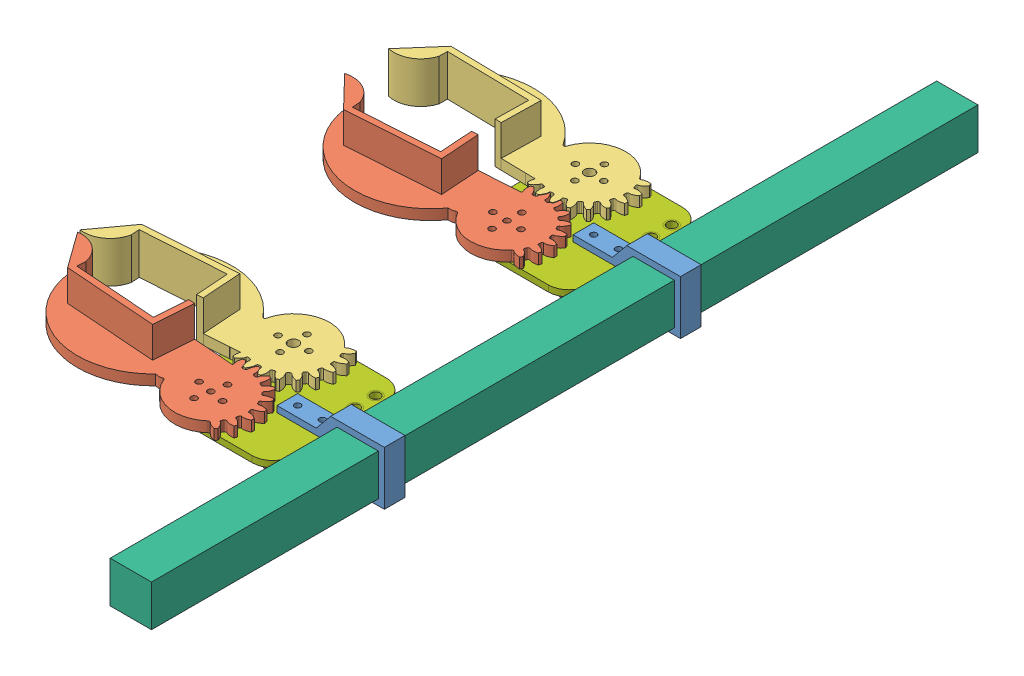
SolidWorks assembly 抓手装配体v1.0, configuration Default. Lengths in mm.
Overall size (156.58 65.63 400).
13 component instances, 7 part files, 36 mates.
Components (placement in the parent):
- M2X20连接件-1: M2X20连接件 [默认] at (-24.8405 13.5666 280.2912) size (52 26 10)
- 右臂直齿M2X20-1: 右臂直齿M2X20 [M2X20] at (-68.8405 21.9166 160.9702) x (0.069464 0 0.997584) z (0 -1 0) size (42.85 107.25 20)
- 左臂直齿M2X20-1: 左臂直齿M2X20 [M2X20] at (-68.8405 17.1166 120.9702) x (0.019311 0 -0.999814) z (0 1 0) size (42.67 107.08 20)
- 35KGservo-2: 35KGservo [默认] at (-58.8405 -8.3834 120.9702) x (-1 0 0) z (0 0 -1) size (62.21 45.03 20.04)
- 舵机圆形头-2: 舵机圆形头 [默认] at (-58.8413 -8.8611 121.095) x (-0.999922 0 -0.012481) z (0.012481 0 -0.999922) size (19.5 4.4 19.5)
- 横杆的简易模型-2: 横杆的简易模型 [默认] at origin size (20 20 400)
- M2X20连接件-2: M2X20连接件 [默认] at (-24.8405 13.4666 136.9702) size (52 26 10)
- M2X20固定舵机盘-3: M2X20固定舵机盘 [默认] at (-23.324 15.0176 132.5027) x (-1 0 0) z (0 -1 0) size (60 65 4.9)
- 右臂直齿M2X20-3: 右臂直齿M2X20 [M2X20] at (-68.8405 22.0166 304.2912) x (-0.073101 0 0.997325) z (0 -1 0) size (42.85 107.25 20)
- 35KGservo-4: 35KGservo [默认] at (-58.8405 -8.2834 264.2912) x (-1 0 0) z (0 0 -1) size (62.21 45.03 20.04)
- 左臂直齿M2X20-3: 左臂直齿M2X20 [M2X20] at (-68.8405 17.2166 264.2912) x (-0.067789 0 -0.9977) z (0 1 0) size (42.67 107.08 20)
- 舵机圆形头-4: 舵机圆形头 [默认] at (-58.8684 -8.7611 263.5451) x (-0.997213 0 0.074603) z (-0.074603 0 -0.997213) size (19.5 4.4 19.5)
- M2X20固定舵机盘-4: M2X20固定舵机盘 [默认] at (-23.324 15.1176 275.8237) x (-1 0 0) z (0 -1 0) size (60 65 4.9)
Mates (geometry in assembly coordinates):
- 重合5: coincident anti-aligned: plane of 35KGservo-2 through (-58.8405 13.1166 120.9702) normal (0 1 0); plane of 舵机圆形头-2 through (-68.8405 13.1166 120.9702) normal (0 -1 0)
- 同心4: concentric anti-aligned: circle of 35KGservo-2; circle of 舵机圆形头-2
- 同心5: concentric aligned: circle of 舵机圆形头-2; circle of M2X20固定舵机盘-3
- 同心7: concentric anti-aligned: cylinder of 35KGservo-2 through (-34.0905 6.0166 125.9702) axis (0 1 0) radius 2.25; cylinder of M2X20固定舵机盘-3 through (-34.0905 15.0176 125.9702) axis (0 -1 0) radius 2.25
- 重合24: coincident anti-aligned: plane of 35KGservo-2 through (-58.8405 12.0166 120.9702) normal (0 1 0); plane of M2X20固定舵机盘-3 through (-23.324 12.0166 132.5027) normal (0 -1 0)
- 重合29: coincident anti-aligned: plane of 左臂直齿M2X20-1 through (-68.8405 17.1166 120.9702) normal (0 -1 0); plane of 舵机圆形头-2 through (-68.8405 17.1166 120.9702) normal (0 1 0)
- 同心15: concentric anti-aligned: cylinder of 左臂直齿M2X20-1 through (-68.8405 22.1166 120.9702) axis (0 -1 0) radius 2.5; circle of 舵机圆形头-2
- 同心16: concentric anti-aligned: circle of 左臂直齿M2X20-1; circle of 舵机圆形头-2
- 重合30: coincident anti-aligned: plane of 右臂直齿M2X20-1 through (-68.8405 16.9166 160.9702) normal (0 -1 0); plane of M2X20固定舵机盘-3 through (-68.8405 16.9166 160.9702) normal (0 1 0)
- 同心17: concentric aligned: cylinder of 右臂直齿M2X20-1 through (-68.8405 16.9166 160.9702) axis (0 1 0) radius 1.5; cylinder of M2X20固定舵机盘-3 through (-68.8405 12.0166 160.9702) axis (0 1 0) radius 2.5
- 同心18: concentric anti-aligned: cylinder of 左臂直齿M2X20-1 through (-61.8418 22.1166 121.1054) axis (0 -1 0) radius 1.5; circle of 舵机圆形头-2
- 重合39: coincident anti-aligned: plane of M2X20连接件-1 through (-21.8405 3.4666 260.2912) normal (0 1 0); plane of 横杆的简易模型-2 through (-1.8405 3.4666 400) normal (0 -1 0)
- 重合40: coincident anti-aligned: plane of M2X20连接件-1 through (-21.8405 23.5666 260.2912) normal (1 0 0); plane of 横杆的简易模型-2 through (-21.8405 23.4666 400) normal (-1 0 0)
- 重合41: coincident anti-aligned: plane of 横杆的简易模型-2 through (-21.8405 23.4666 400) normal (-1 0 0); plane of M2X20连接件-2 through (-21.8405 23.4666 116.9702) normal (1 0 0)
- 重合42: coincident anti-aligned: plane of 横杆的简易模型-2 through (-21.8405 23.4666 400) normal (0 1 0); plane of M2X20连接件-2 through (-1.7405 23.4666 116.9702) normal (0 -1 0)
- 重合46: coincident anti-aligned: plane of M2X20连接件-2 through (-50.8405 15.0166 146.9702) normal (0 -1 0); plane of M2X20固定舵机盘-3 through (-23.324 15.0166 132.5027) normal (0 1 0)
- 锁定2: lock: unknown of 横杆的简易模型-2; unknown of M2X20连接件-2
- 锁定3: lock: unknown of M2X20连接件-1; unknown of 横杆的简易模型-2
- 同心21: concentric aligned: circle of 舵机圆形头-4; circle of M2X20固定舵机盘-4
- 同心22: concentric anti-aligned: cylinder of 35KGservo-4 through (-34.0905 6.1166 269.2912) axis (0 1 0) radius 2.25; cylinder of M2X20固定舵机盘-4 through (-34.0905 15.1176 269.2912) axis (0 -1 0) radius 2.25
- 同心23: concentric anti-aligned: cylinder of 左臂直齿M2X20-3 through (-68.8405 22.2166 264.2912) axis (0 -1 0) radius 2.5; circle of 舵机圆形头-4
- 重合50: coincident anti-aligned: plane of 35KGservo-4 through (-58.8405 13.2166 264.2912) normal (0 1 0); plane of 舵机圆形头-4 through (-68.8405 13.2166 264.2912) normal (0 -1 0)
- 同心24: concentric anti-aligned: circle of 35KGservo-4; circle of 舵机圆形头-4
- 同心25: concentric anti-aligned: circle of 左臂直齿M2X20-3; circle of 舵机圆形头-4
- 同心26: concentric aligned: cylinder of 右臂直齿M2X20-3 through (-68.8405 17.0166 304.2912) axis (0 1 0) radius 1.5; cylinder of M2X20固定舵机盘-4 through (-68.8405 12.1166 304.2912) axis (0 1 0) radius 2.5
- 重合51: coincident anti-aligned: plane of 右臂直齿M2X20-3 through (-68.8405 17.0166 304.2912) normal (0 -1 0); plane of M2X20固定舵机盘-4 through (-68.8405 17.0166 304.2912) normal (0 1 0)
- 同心27: concentric anti-aligned: cylinder of 左臂直齿M2X20-3 through (-61.8566 22.2166 263.8166) axis (0 -1 0) radius 1.5; circle of 舵机圆形头-4
- 重合52: coincident anti-aligned: plane of 左臂直齿M2X20-3 through (-68.8405 17.2166 264.2912) normal (0 -1 0); plane of 舵机圆形头-4 through (-68.8405 17.2166 264.2912) normal (0 1 0)
- 重合53: coincident anti-aligned: plane of 35KGservo-4 through (-58.8405 12.1166 264.2912) normal (0 1 0); plane of M2X20固定舵机盘-4 through (-23.324 12.1166 275.8237) normal (0 -1 0)
- 同心36: concentric anti-aligned: cylinder of M2X20连接件-1 through (-45.8405 4.7739 285.2912) axis (0 1 0) radius 1.5; cylinder of M2X20固定舵机盘-4 through (-45.8405 22.1166 285.2912) axis (0 -1 0) radius 1.5
- 重合58: coincident anti-aligned: plane of M2X20连接件-1 through (-50.8405 15.1166 290.2912) normal (0 -1 0); plane of M2X20固定舵机盘-4 through (-23.324 15.1166 275.8237) normal (0 1 0)
- 同心37: concentric anti-aligned: circle of M2X20连接件-1; circle of M2X20固定舵机盘-4
- 齿轮配合6: gear = 5 : 5 mm: circle of 左臂直齿M2X20-3; circle of 右臂直齿M2X20-3
- 同心38: concentric anti-aligned: circle of M2X20连接件-2; cylinder of M2X20固定舵机盘-3 through (-45.8405 22.0166 141.9702) axis (0 -1 0) radius 1.5
- 同心40: concentric anti-aligned: cylinder of M2X20连接件-2 through (-33.8405 4.6739 141.9702) axis (0 1 0) radius 1.5; cylinder of M2X20固定舵机盘-3 through (-33.8405 22.0166 141.9702) axis (0 -1 0) radius 1.5
- 齿轮配合7: gear = 5 : 5 mm: circle of 右臂直齿M2X20-1; cylinder of 左臂直齿M2X20-1 through (-68.8405 22.1166 120.9702) axis (0 -1 0) radius 2.5
